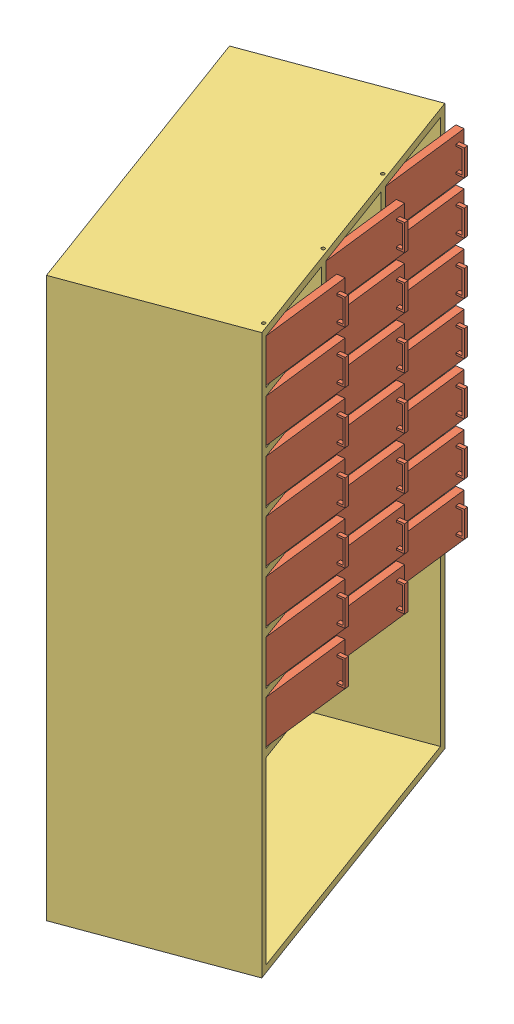
SolidWorks assembly Assem1, configuration Default. Lengths in mm.
Overall size (720.73 1500 934.46).
64 component instances, 3 part files, 7 mates.
Components (placement in the parent):
- pivot mentese-1: pivot mentese [Varsayılan] at (-31.4104 29.139 30.8368) size (13 32 13)
- door-1: door [Default] at (-54.9505 -10.861 -80.8992) x (0.992814 0 -0.119665) z (0.119665 0 0.992814) size (40 115 247.5)
- pivot mentese-2: pivot mentese [Varsayılan] at (-31.4104 -50.861 30.8368) x (0.057246 0 -0.99836) z (-0.99836 0 -0.057246) size (13 32 13)
- storage_frame-1: storage_frame [Default] at (-319.6643 -930.861 -129.2717) x (-0.346196 0 -0.938162) z (0.938162 0 -0.346196) size (830 1500 450)
- pivot mentese-3: pivot mentese [Varsayılan] at (-31.4104 -110.861 30.8368) size (13 32 13)
- pivot mentese-4: pivot mentese [Varsayılan] at (-31.4104 -250.861 30.8368) size (13 32 13)
- pivot mentese-5: pivot mentese [Varsayılan] at (-31.4104 -390.861 30.8368) size (13 32 13)
- pivot mentese-6: pivot mentese [Varsayılan] at (-31.4104 -530.861 30.8368) size (13 32 13)
- pivot mentese-7: pivot mentese [Varsayılan] at (-31.4104 -670.861 30.8368) size (13 32 13)
- pivot mentese-8: pivot mentese [Varsayılan] at (-31.4104 -810.861 30.8368) size (13 32 13)
- pivot mentese-9: pivot mentese [Varsayılan] at (-31.4104 -190.861 30.8368) x (0.057246 0 -0.99836) z (-0.99836 0 -0.057246) size (13 32 13)
- pivot mentese-10: pivot mentese [Varsayılan] at (-31.4104 -330.861 30.8368) x (0.057246 0 -0.99836) z (-0.99836 0 -0.057246) size (13 32 13)
- pivot mentese-11: pivot mentese [Varsayılan] at (-31.4104 -470.861 30.8368) x (0.057246 0 -0.99836) z (-0.99836 0 -0.057246) size (13 32 13)
- pivot mentese-12: pivot mentese [Varsayılan] at (-31.4104 -610.861 30.8368) x (0.057246 0 -0.99836) z (-0.99836 0 -0.057246) size (13 32 13)
- pivot mentese-13: pivot mentese [Varsayılan] at (-31.4104 -750.861 30.8368) x (0.057246 0 -0.99836) z (-0.99836 0 -0.057246) size (13 32 13)
- pivot mentese-14: pivot mentese [Varsayılan] at (-31.4104 -890.861 30.8368) x (0.057246 0 -0.99836) z (-0.99836 0 -0.057246) size (13 32 13)
- door-2: door [Default] at (-54.9505 -150.861 -80.8992) x (0.992814 0 -0.119665) z (0.119665 0 0.992814) size (40 115 247.5)
- door-3: door [Default] at (-54.9505 -290.861 -80.8992) x (0.992814 0 -0.119665) z (0.119665 0 0.992814) size (40 115 247.5)
- door-4: door [Default] at (-54.9505 -430.861 -80.8992) x (0.992814 0 -0.119665) z (0.119665 0 0.992814) size (40 115 247.5)
- door-5: door [Default] at (-54.9505 -570.861 -80.8992) x (0.992814 0 -0.119665) z (0.119665 0 0.992814) size (40 115 247.5)
- door-6: door [Default] at (-54.9505 -710.861 -80.8992) x (0.992814 0 -0.119665) z (0.119665 0 0.992814) size (40 115 247.5)
- door-7: door [Default] at (-54.9505 -850.861 -80.8992) x (0.992814 0 -0.119665) z (0.119665 0 0.992814) size (40 115 247.5)
- pivot mentese-43: pivot mentese [Varsayılan] at (-124.8833 29.139 -222.467) size (13 32 13)
- pivot mentese-44: pivot mentese [Varsayılan] at (-218.3562 29.139 -475.7709) size (13 32 13)
- pivot mentese-45: pivot mentese [Varsayılan] at (-124.8833 -50.861 -222.467) x (0.057246 0 -0.99836) z (-0.99836 0 -0.057246) size (13 32 13)
- pivot mentese-46: pivot mentese [Varsayılan] at (-218.3562 -50.861 -475.7709) x (0.057246 0 -0.99836) z (-0.99836 0 -0.057246) size (13 32 13)
- door-22: door [Default] at (-148.4234 -10.861 -334.203) x (0.992814 0 -0.119665) z (0.119665 0 0.992814) size (40 115 247.5)
- door-23: door [Default] at (-241.8963 -10.861 -587.5068) x (0.992814 0 -0.119665) z (0.119665 0 0.992814) size (40 115 247.5)
- pivot mentese-47: pivot mentese [Varsayılan] at (-124.8833 -110.861 -222.467) size (13 32 13)
- pivot mentese-48: pivot mentese [Varsayılan] at (-218.3562 -110.861 -475.7709) size (13 32 13)
- pivot mentese-49: pivot mentese [Varsayılan] at (-124.8833 -250.861 -222.467) size (13 32 13)
- pivot mentese-50: pivot mentese [Varsayılan] at (-218.3562 -250.861 -475.7709) size (13 32 13)
- pivot mentese-51: pivot mentese [Varsayılan] at (-124.8833 -390.861 -222.467) size (13 32 13)
- pivot mentese-52: pivot mentese [Varsayılan] at (-218.3562 -390.861 -475.7709) size (13 32 13)
- pivot mentese-53: pivot mentese [Varsayılan] at (-124.8833 -530.861 -222.467) size (13 32 13)
- pivot mentese-54: pivot mentese [Varsayılan] at (-218.3562 -530.861 -475.7709) size (13 32 13)
- pivot mentese-55: pivot mentese [Varsayılan] at (-124.8833 -670.861 -222.467) size (13 32 13)
- pivot mentese-56: pivot mentese [Varsayılan] at (-218.3562 -670.861 -475.7709) size (13 32 13)
- pivot mentese-57: pivot mentese [Varsayılan] at (-124.8833 -810.861 -222.467) size (13 32 13)
- pivot mentese-58: pivot mentese [Varsayılan] at (-218.3562 -810.861 -475.7709) size (13 32 13)
- pivot mentese-59: pivot mentese [Varsayılan] at (-124.8833 -190.861 -222.467) x (0.057246 0 -0.99836) z (-0.99836 0 -0.057246) size (13 32 13)
- pivot mentese-60: pivot mentese [Varsayılan] at (-218.3562 -190.861 -475.7709) x (0.057246 0 -0.99836) z (-0.99836 0 -0.057246) size (13 32 13)
- pivot mentese-61: pivot mentese [Varsayılan] at (-124.8833 -330.861 -222.467) x (0.057246 0 -0.99836) z (-0.99836 0 -0.057246) size (13 32 13)
- pivot mentese-62: pivot mentese [Varsayılan] at (-218.3562 -330.861 -475.7709) x (0.057246 0 -0.99836) z (-0.99836 0 -0.057246) size (13 32 13)
- pivot mentese-63: pivot mentese [Varsayılan] at (-124.8833 -470.861 -222.467) x (0.057246 0 -0.99836) z (-0.99836 0 -0.057246) size (13 32 13)
- pivot mentese-64: pivot mentese [Varsayılan] at (-218.3562 -470.861 -475.7709) x (0.057246 0 -0.99836) z (-0.99836 0 -0.057246) size (13 32 13)
- pivot mentese-65: pivot mentese [Varsayılan] at (-124.8833 -610.861 -222.467) x (0.057246 0 -0.99836) z (-0.99836 0 -0.057246) size (13 32 13)
- pivot mentese-66: pivot mentese [Varsayılan] at (-218.3562 -610.861 -475.7709) x (0.057246 0 -0.99836) z (-0.99836 0 -0.057246) size (13 32 13)
- pivot mentese-67: pivot mentese [Varsayılan] at (-124.8833 -750.861 -222.467) x (0.057246 0 -0.99836) z (-0.99836 0 -0.057246) size (13 32 13)
- pivot mentese-68: pivot mentese [Varsayılan] at (-218.3562 -750.861 -475.7709) x (0.057246 0 -0.99836) z (-0.99836 0 -0.057246) size (13 32 13)
- pivot mentese-69: pivot mentese [Varsayılan] at (-124.8833 -890.861 -222.467) x (0.057246 0 -0.99836) z (-0.99836 0 -0.057246) size (13 32 13)
- pivot mentese-70: pivot mentese [Varsayılan] at (-218.3562 -890.861 -475.7709) x (0.057246 0 -0.99836) z (-0.99836 0 -0.057246) size (13 32 13)
- door-24: door [Default] at (-148.4234 -150.861 -334.203) x (0.992814 0 -0.119665) z (0.119665 0 0.992814) size (40 115 247.5)
- door-25: door [Default] at (-241.8963 -150.861 -587.5068) x (0.992814 0 -0.119665) z (0.119665 0 0.992814) size (40 115 247.5)
- door-26: door [Default] at (-148.4234 -290.861 -334.203) x (0.992814 0 -0.119665) z (0.119665 0 0.992814) size (40 115 247.5)
- door-27: door [Default] at (-241.8963 -290.861 -587.5068) x (0.992814 0 -0.119665) z (0.119665 0 0.992814) size (40 115 247.5)
- door-28: door [Default] at (-148.4234 -430.861 -334.203) x (0.992814 0 -0.119665) z (0.119665 0 0.992814) size (40 115 247.5)
- door-29: door [Default] at (-241.8963 -430.861 -587.5068) x (0.992814 0 -0.119665) z (0.119665 0 0.992814) size (40 115 247.5)
- door-30: door [Default] at (-148.4234 -570.861 -334.203) x (0.992814 0 -0.119665) z (0.119665 0 0.992814) size (40 115 247.5)
- door-31: door [Default] at (-241.8963 -570.861 -587.5068) x (0.992814 0 -0.119665) z (0.119665 0 0.992814) size (40 115 247.5)
- door-32: door [Default] at (-148.4234 -710.861 -334.203) x (0.992814 0 -0.119665) z (0.119665 0 0.992814) size (40 115 247.5)
- door-33: door [Default] at (-241.8963 -710.861 -587.5068) x (0.992814 0 -0.119665) z (0.119665 0 0.992814) size (40 115 247.5)
- door-34: door [Default] at (-148.4234 -850.861 -334.203) x (0.992814 0 -0.119665) z (0.119665 0 0.992814) size (40 115 247.5)
- door-35: door [Default] at (-241.8963 -850.861 -587.5068) x (0.992814 0 -0.119665) z (0.119665 0 0.992814) size (40 115 247.5)
Mates (geometry in assembly coordinates):
- Concentric1: concentric anti-aligned: cone of pivot mentese-1 through (-31.4104 46.639 30.8368) axis (0 -1 0); cylinder of door-1 through (-31.4104 29.139 30.8368) axis (0 1 0) radius 4.4
- Coincident1: coincident anti-aligned: plane of pivot mentese-1 through (-31.4104 29.139 30.8368) normal (0 -1 0); plane of door-1 through (-31.4104 29.139 30.8368) normal (0 1 0)
- Concentric2: concentric anti-aligned: cylinder of door-1 through (-31.4104 -50.861 30.8368) axis (0 -1 0) radius 4.4; cone of pivot mentese-2 through (-31.4104 -68.361 30.8368) axis (0 1 0)
- Coincident2: coincident anti-aligned: plane of door-1 through (-31.4104 -50.861 30.8368) normal (0 -1 0); plane of pivot mentese-2 through (-31.4104 -50.861 30.8368) normal (0 1 0)
- Concentric3: concentric aligned: cylinder of pivot mentese-1 through (-31.4104 57.139 30.8368) axis (0 -1 0) radius 3; cylinder of storage_frame-1 through (-31.4104 81.584 30.8368) axis (0 -1 0) radius 4.4
- Concentric4: concentric aligned: circle of pivot mentese-1; circle of storage_frame-1
- Coincident3: coincident anti-aligned: plane of pivot mentese-1 through (-37.9104 49.139 30.8368) normal (0 1 0); plane of storage_frame-1 through (-319.6643 49.139 -129.2717) normal (0 -1 0)
